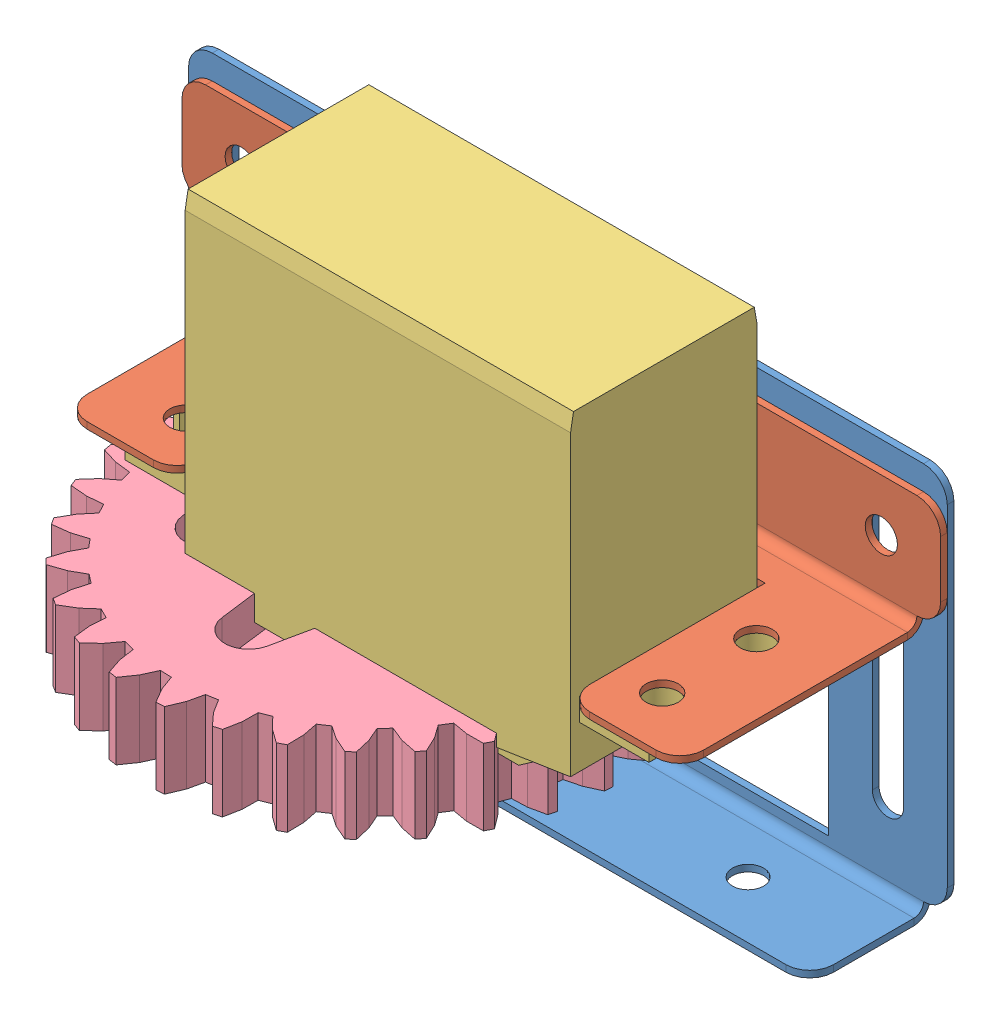
SolidWorks assembly 01 Servo Assembly v2, configuration Default. Lengths in mm.
Overall size (80 52.73 51.77).
4 component instances, 4 part files, 10 mates.
Components (placement in the parent):
- Servo Bracket 2.1-1: Servo Bracket 2.1 [Default] at origin size (80 41.7 12.7)
- Servo Bracket 2.2-1: Servo Bracket 2.2 [Default] at (5 5.4435 13.7) size (80 12.7 25.7)
- Servo Futaba S3003-1: Servo Futaba S3003 [Default] at (4.9999 -4.7307 15.1998) x (0 0 -1) z (0 1 0) size (19.69 55.27 37.39)
- Printed Servo Gear-1: Printed Servo Gear [Default] at (-52.9975 -2.0818 77.1357) x (0.999204 0 0.039897) z (0 1 0) size (50 49.82 8)
Mates (geometry in assembly coordinates):
- Coincident1: coincident aligned: plane of Servo Bracket 2.1-1 through (0 0 0) normal (0 0 1); plane of assembly through (0 0 0) normal (0 0 1)
- Coincident2: coincident aligned: plane of Servo Bracket 2.1-1 through (0 0 0) normal (0 1 0); plane of assembly through (0 0 0) normal (0 1 0)
- Coincident3: coincident aligned: plane of Servo Bracket 2.1-1 through (0 0 0) normal (1 0 0); plane of assembly through (0 0 0) normal (1 0 0)
- Coincident4: coincident anti-aligned: plane of Servo Bracket 2.1-1 through (0 0 0) normal (0 0 1); plane of Servo Bracket 2.2-1 through (5 5.4435 0) normal (0 0 -1)
- Coincident5: coincident: plane of Servo Bracket 2.1-1 through (-33.75 0 0) normal (1 0 0); line of Servo Bracket 2.2-1 through (-33.75 11.9435 0) axis (0 0 1)
- Coincident6: coincident: plane of Servo Bracket 2.1-1 through (33.75 0 0) normal (1 0 0); line of Servo Bracket 2.2-1 through (33.75 11.9435 0) axis (0 0 1)
- Coincident7: coincident anti-aligned: plane of Servo Bracket 2.2-1 through (5 4.7435 13.7) normal (0 -1 0); plane of Servo Futaba S3003-1 through (-22.6353 4.7435 24.0898) normal (0 1 0)
- Concentric3: concentric aligned: circle of Servo Bracket 2.2-1; cylinder of Servo Futaba S3003-1 through (30.1078 31.0335 20.1655) axis (0 -1 0) radius 2.2479
- Concentric4: concentric aligned: circle of Servo Bracket 2.2-1; cylinder of Servo Futaba S3003-1 through (-20.108 31.0335 20.1655) axis (0 -1 0) radius 2.2479
- Concentric5: concentric anti-aligned: cylinder of Servo Futaba S3003-1 through (-4.4616 3.6437 15.1998) axis (0 -1 0) radius 2.9591; cylinder of Printed Servo Gear-1 through (-4.4616 -10.0818 15.1998) axis (0 1 0) radius 1.625
